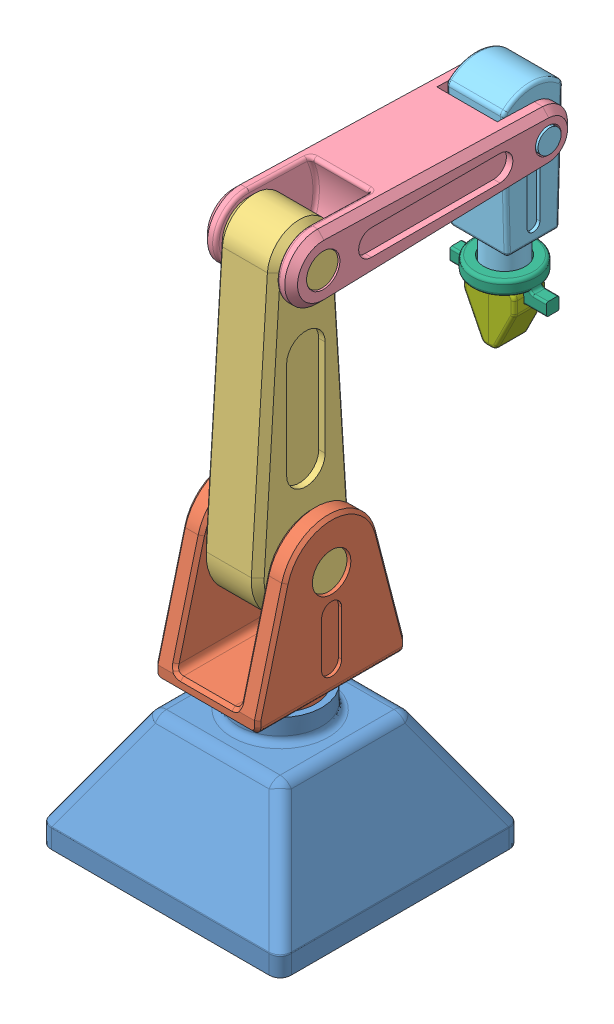
SolidWorks assembly robotic_arm, configuration Default. Lengths in mm.
Overall size (375.12 870 587.56).
8 component instances, 7 part files, 24 mates.
Components (placement in the parent):
- Base-1: Base [Default] at origin size (375.12 215 375.12)
- Link_1-1: Link_1 [Default] x (0 0 1) z (-1 0 0) size (230 280 160)
- Link_2-1: Link_2 [Default] at (-5 0 0) x (0 0 -1) z (1 0 0) size (150 525 160)
- Link_3-1: Link_3 [Default] at (-3 0 0) x (0 0 1) z (-1 0 0) size (440 100 140)
- Link_4-1: Link_4 [Default] at (-1 750 -750) x (0 1 0) z (1 0 0) size (265 92.4 140)
- Link_5-1: Link_5 [Default] at (-1 752 50) x (0 1 0) z (-1 0 0) size (42 100 150)
- link_6-1: link_6 [Default] at (-1 752 50) x (0 1 0) z (-1 0 0) size (90 50 40)
- link_6-2: link_6 [Default] at (-1 752 -750) x (0 1 0) z (1 0 0) size (90 50 40)
Mates (geometry in assembly coordinates):
- Concentric1: concentric anti-aligned: cylinder of Base-1 through (0 -190 0) axis (0 -1 0) radius 55; cylinder of Link_1-1 through (0 -205 0) axis (0 1 0) radius 55
- Coincident1: coincident anti-aligned: plane of Base-1 through (0 -205 0) normal (0 1 0); plane of Link_1-1 through (0 -205 0) normal (0 -1 0)
- Concentric3: concentric anti-aligned: cylinder of Link_1-1 through (80 0 0) axis (-1 0 0) radius 30; cylinder of Link_2-1 through (-167.0244 0 0) axis (1 0 0) radius 29
- Coincident4: coincident anti-aligned: plane of Link_1-1 through (-50 0 0) normal (1 0 0); plane of Link_2-1 through (-50 0 0) normal (-1 0 0)
- Concentric4: concentric aligned: axis of Link_2-1 through (-50 400 0) axis (-1 0 0); cylinder of Link_3-1 through (518.2206 400 0) axis (-1 0 0) radius 26
- Coincident5: coincident anti-aligned: plane of Link_2-1 through (-50 0 0) normal (-1 0 0); plane of Link_3-1 through (-50 400 -350) normal (1 0 0)
- Concentric5: concentric aligned: cylinder of Link_3-1 through (518.2206 400 -350) axis (-1 0 0) radius 20; cylinder of Link_4-1 through (119.9117 400 -350) axis (-1 0 0) radius 18
- Coincident6: coincident anti-aligned: plane of Link_3-1 through (44 400 -350) normal (-1 0 0); plane of Link_4-1 through (44 400 -350) normal (1 0 0)
- Concentric7: concentric anti-aligned: cylinder of Link_4-1 through (-1 200 -350) axis (0 1 0) radius 30; cylinder of Link_5-1 through (-1 212 -350) axis (0 -1 0) radius 32
- Coincident8: coincident anti-aligned: plane of Link_4-1 through (-1 200 -350) normal (0 -1 0); plane of Link_5-1 through (-1 200 -350) normal (0 1 0)
- Coincident9: coincident anti-aligned: plane of Link_5-1 through (74 170 -340) normal (0 0 1); plane of link_7-1 through (-15.9208 -168.5813 154.9775) normal (-0.581388 0.453021 0.675841)
- Coincident11: coincident anti-aligned: plane of Link_5-1 through (74 170 -340) normal (0 0 1); plane of link_7-1 through (-15.9208 -168.5813 154.9775) normal (-0.581388 0.453021 0.675841)
- Coincident12: coincident anti-aligned: plane of Link_5-1 through (-1 170 50) normal (0 -1 0); plane of link_7-1 through (-48.1159 -43.521 -533.6061) normal (0.444908 -0.518451 0.730251)
- Coincident17: coincident anti-aligned: plane of Link_5-1 through (74 170 -340) normal (0 0 1); plane of link_6-1 through (39 752 -340) normal (0 0 -1)
- Coincident18: coincident anti-aligned: plane of Link_5-1 through (-1 170 50) normal (0 -1 0); plane of link_6-1 through (39 170 50) normal (0 1 0)
- Coincident19: coincident aligned: plane of Link_5-1 through (74 170 -340) normal (0 0 1); plane of link_7-4 through (292.8138 96.4566 -274.1368) normal (-0.410779 -0.869649 -0.27381)
- Coincident26: coincident anti-aligned: plane of Link_5-1 through (74 170 -340) normal (0 0 1); plane of link_7-5 through (28.5131 -57.1282 77.3369) normal (-0.69099 0.350494 0.632208)
- Coincident27: coincident anti-aligned: plane of Link_5-1 through (-1 170 50) normal (0 -1 0); plane of link_7-5 through (28.7515 72.5006 -611.1544) normal (0.462625 -0.457597 0.759331)
- Parallel5: parallel aligned: plane of Base-1 through (186.6025 -405 -169.282) normal (1 0 0); plane of Link_1-1 through (80 -165 -115) normal (1 0 0)
- Parallel16: parallel anti-aligned: line of Link_1-1 through (-80 -125 15.6405) axis (0 1 0); line of Link_2-1 through (-50 275 30) axis (0 -1 0)
- Perpendicular1: perpendicular: plane of Link_2-1 through (30 275 -30) normal (0 0 1); plane of Link_3-1 through (57 380 -275) normal (0 1 0)
- Coincident38: coincident anti-aligned: plane of Link_4-1; plane of Link_5-1
- Coincident39: coincident aligned: plane of Link_5-1 through (-1 732.0297 66.7257) normal (-1 0 0); plane of link_6-1 through (-1 732.0297 66.7257) normal (-1 0 0)
- Perpendicular4: perpendicular: plane of Link_3-1 through (57 380 -275) normal (0 1 0); line of Link_4-1 through (44 355 -340) axis (0 -1 0)
